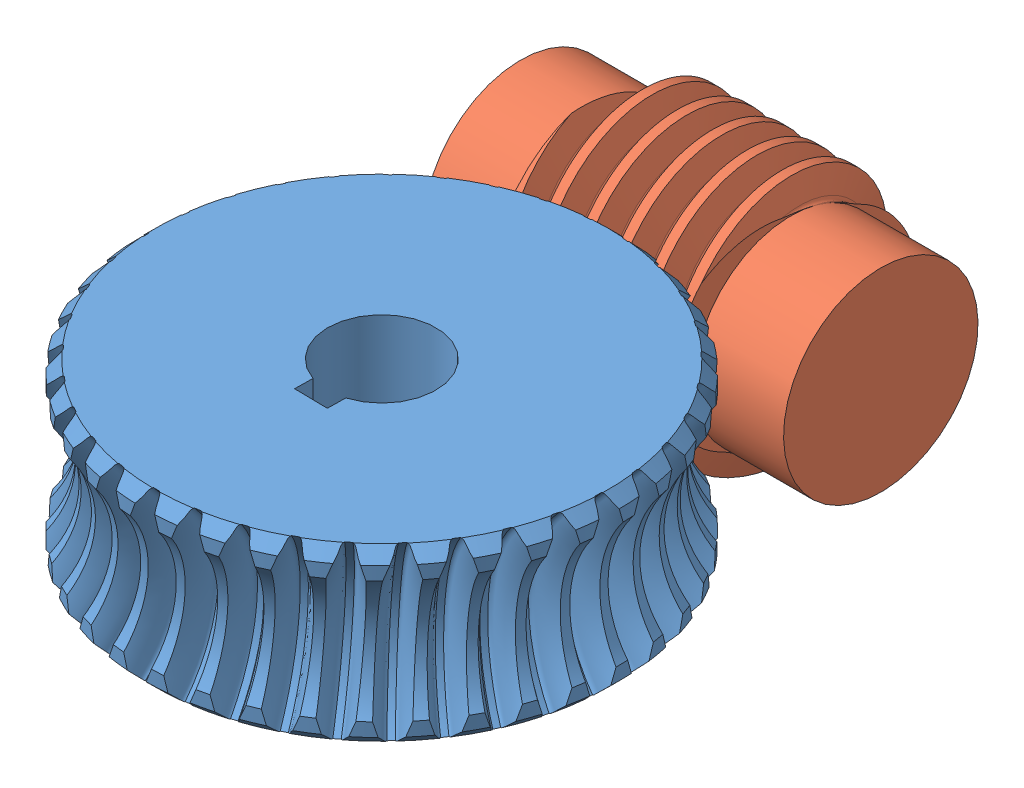
SolidWorks assembly 装配体3, configuration 默认. Lengths in mm.
Overall size (47.19 22.83 79.14).
2 component instances, 2 part files, 5 mates.
Components (placement in the parent):
- 蜗轮37×1-1: 蜗轮37×1 [默认] at (0 0 28.5) x (0.999869 0 0.016175) z (0 -1 0) size (44.13 60.84 20.26)
- 蜗杆2×1-1: 蜗杆2×1 [默认] at (-7.9 0 0) x (1 0 0) z (0 -0.022259 0.999752) size (40.5 22.33 22.57)
Mates (geometry in assembly coordinates):
- 同心1: concentric: cylinder of 蜗轮37×1-1 through (0 10.549 28.5) axis (0 1 0) radius 4.875
- 平行1: parallel aligned: plane of 蜗轮37×1-1 through (-20.3641 7.7 28.1706) normal (0 1 0)
- 同心3: concentric aligned: cylinder of 蜗杆2×1-1 through (-16 0 0) axis (1 0 0) radius 8.75
- 距离2: distance = 16 mm: plane of assembly; point of assembly; plane of 蜗杆2×1-1 through (-16 0 0) normal (-1 0 0)
- 距离3: distance = 7.7 mm: plane of 蜗轮37×1-1 through (-20.3641 7.7 28.1706) normal (0 1 0); cylinder of 蜗杆2×1-1 through (-16 0 0) axis (1 0 0) radius 8.75
